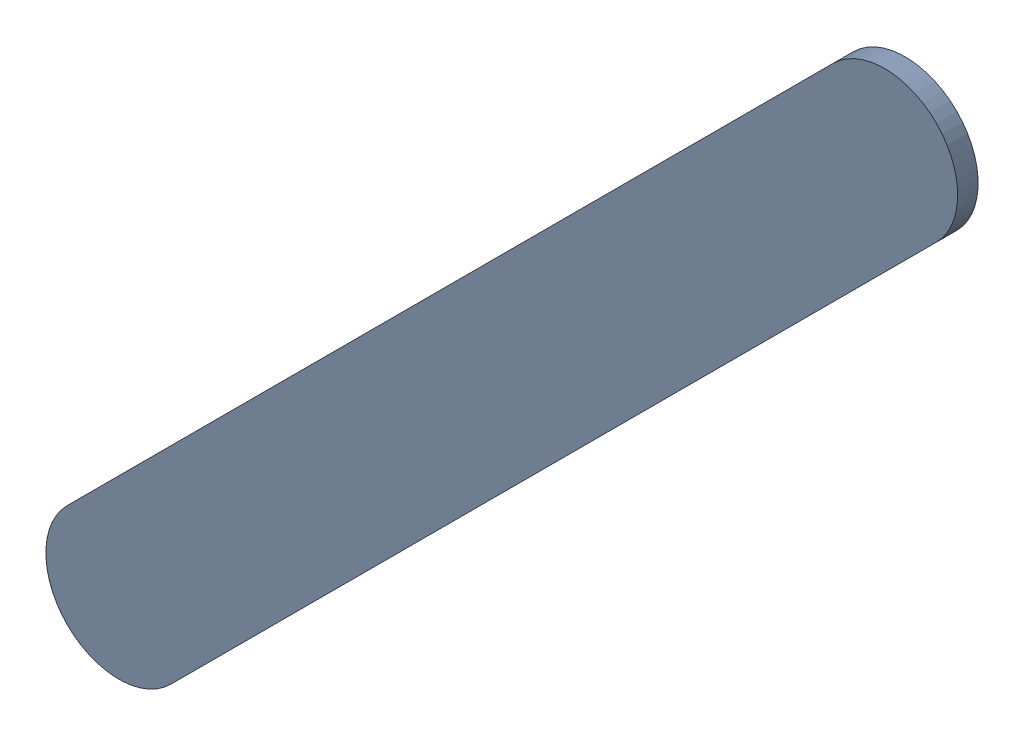
SolidWorks assembly Track (22.393mm,27.093mm)(23.725mm,28.425mm) on Top Layer, configuration Predeterminado. Lengths in mm.
Overall size (1.59 1.59 0.04).
2 component instances, 1 part files, 0 mates.
Components (placement in the parent):
- Track (22.393mm,27.093mm)(23.725mm,28.425mm) on Top Layer-1-1: Track (22.393mm,27.093mm)(23.725mm,28.425mm) on Top Layer-1 [Predeterminado] at (-68.317 -44.187 -0.0457) size (1.59 1.59 0.04)
  - Track (22.393mm,27.093mm)(23.725mm,28.425mm) on Top Layer-Part-1-1: Track (22.393mm,27.093mm)(23.725mm,28.425mm) on Top Layer-Part-1 [Predeterminado] at origin size (1.59 1.59 0.04)
